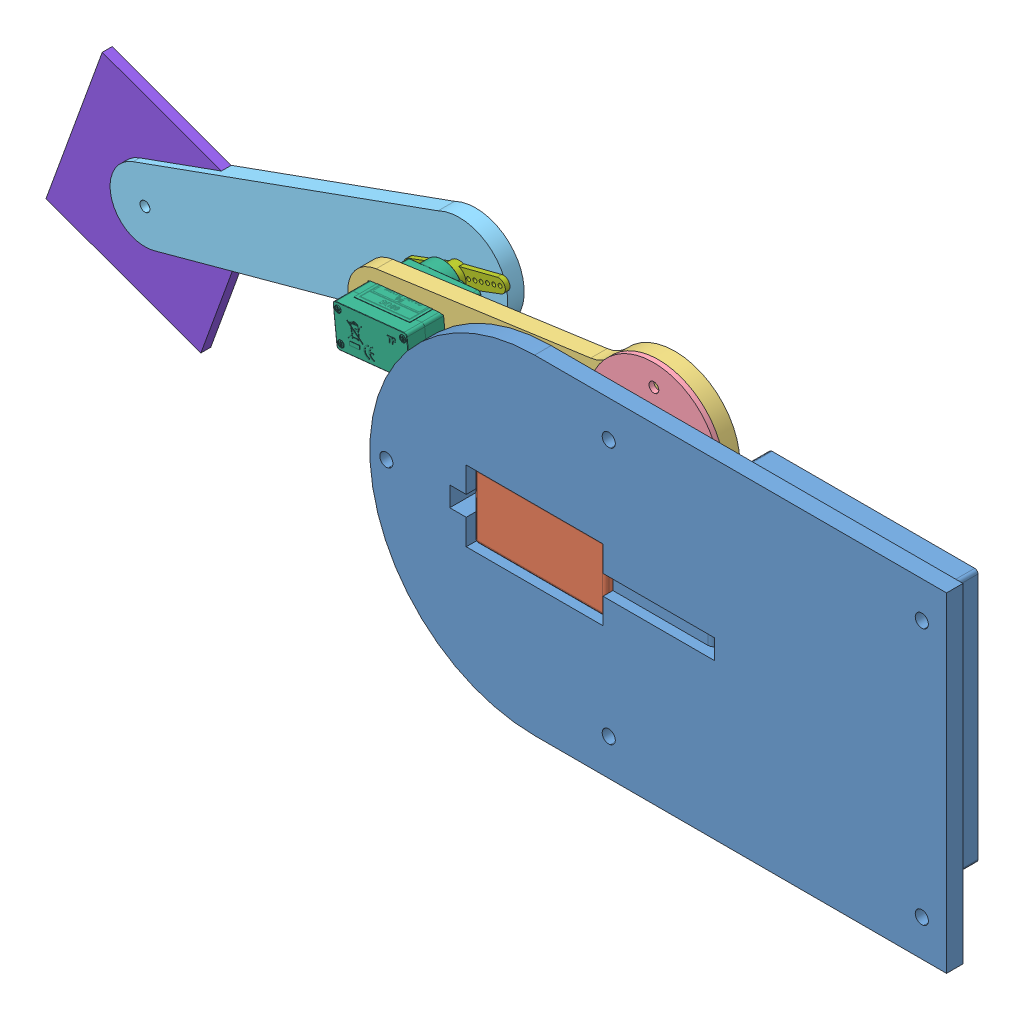
SolidWorks assembly 2 link manipulor, configuration Default. Lengths in mm.
Overall size (343.82 120.64 73.55).
8 component instances, 8 part files, 21 mates.
Components (placement in the parent):
- base-1: base [Default] at (52.7879 97.5917 136.6842) size (175 100 32)
- ServoMG996R-1: ServoMG996R [Default] at (52.7879 97.5917 126.5842) size (53.6 20 44.5)
- link1-1: link1 [Default] at (-0.7592 92.9782 116.0842) x (0.994435 0.105353 0) z (0 0 1) size (114.49 39.44 5)
- ServoMount-1: ServoMount [Default] at (76.5728 26.5748 121.0842) x (0.999979 -0.006541 0) z (0 0 1) size (40 40 5.5)
- link2-1: link2 [Default] at (-88.917 73.2046 95.1342) x (-0.953672 -0.300847 0) z (-0.300847 0.953672 0) size (125.32 5 29.44)
- SG90 - Micro Servo 9g - Tower Pro.1-2: SG90 - Micro Servo 9g - Tower Pro.1 [Peça] at (-33.5163 89.6084 121.2342) x (0.994435 0.105353 0) z (-0.105353 0.994435 0) size (32.1 29.95 12.4)
- SG90 - Micro Servo 9g - Tower Pro.3-1: SG90 - Micro Servo 9g - Tower Pro.3 [Peça] at (-38.6376 89.0659 100.1342) x (0.953672 0.300847 0) z (-0.300847 0.953672 0) size (32.1 3.8 6.9)
- Kotak-1: Kotak [Default] at (-134.0048 58.9811 95.1342) x (0.341317 0.939948 0) z (0 0 1) size (50 50 3)
Mates (geometry in assembly coordinates):
- Concentric3: concentric anti-aligned: cylinder of base-1 through (28.3879 92.5917 151.6842) axis (0 0 -1) radius 1; cylinder of ServoMG996R-1 through (28.3879 92.5917 134.6842) axis (0 0 1) radius 2.2
- Concentric4: concentric anti-aligned: cylinder of base-1 through (28.3879 102.5917 151.6842) axis (0 0 -1) radius 1; cylinder of ServoMG996R-1 through (28.3879 102.5917 134.6842) axis (0 0 1) radius 2.2
- Coincident7: coincident anti-aligned: plane of base-1 through (52.7879 97.5917 136.6842) normal (0 0 -1); plane of ServoMG996R-1 through (52.7879 97.5917 136.6842) normal (0 0 1)
- Concentric5: concentric anti-aligned: cylinder of ServoMG996R-1 through (42.7879 97.5917 122.5842) axis (0 0 1) radius 3; cylinder of ServoMount-1 through (42.7879 97.5917 126.5842) axis (0 0 -1) radius 3
- Coincident8: coincident anti-aligned: plane of ServoMG996R-1 through (42.7879 97.5917 122.5842) normal (0 0 -1); plane of ServoMount-1 through (42.7879 97.5917 122.5842) normal (0 0 1)
- Concentric6: concentric anti-aligned: cylinder of link1-1 through (42.7879 97.5917 115.0842) axis (0 0 1) radius 4.5; cylinder of ServoMount-1 through (42.7879 97.5917 122.5842) axis (0 0 -1) radius 1
- Coincident9: coincident anti-aligned: plane of link1-1 through (-0.7592 92.9782 121.0842) normal (0 0 1); plane of ServoMount-1 through (42.7879 97.5917 121.0842) normal (0 0 -1)
- Coincident13: coincident anti-aligned: plane of link2-1 through (-38.6376 89.0659 100.1342) normal (0 0 1); plane of ServoMount2-1 through (-41.4225 92.5523 88.6657) normal (0 0 -1)
- Concentric13: concentric aligned: cylinder of link2-1 through (-38.6376 89.0659 100.1342) axis (0 0 -1) radius 1.05; cylinder of ServoMount2-1 through (-41.4225 92.5523 90.1657) axis (0 0 -1) radius 15
- Coincident14: coincident anti-aligned: plane of link1-1 through (-45.3252 94.2904 121.0842) normal (0.105353 -0.994435 0); plane of SG90 - Micro Servo 9g - Tower Pro.1-1 through (-46.4443 118.3601 113.5842) normal (0.162415 0.986723 0)
- Coincident15: coincident anti-aligned: plane of link1-1 through (-22.4532 96.7135 121.0842) normal (-0.994435 -0.105353 0); plane of SG90 - Micro Servo 9g - Tower Pro.1-1 through (-20.4836 113.2255 116.0842) normal (0.986723 -0.162415 0)
- Coincident16: coincident anti-aligned: plane of link1-1 through (-0.7592 92.9782 116.0842) normal (0 0 -1); plane of SG90 - Micro Servo 9g - Tower Pro.1-1 through (-46.5824 117.5214 116.0842) normal (0 0 1)
- Concentric14: concentric aligned: circle of SG90 - Micro Servo 9g - Tower Pro.1-2; circle of SG90 - Micro Servo 9g - Tower Pro.3-1
- Coincident18: coincident anti-aligned: plane of link1-1 through (-44.061 82.3572 121.0842) normal (-0.105353 0.994435 0); plane of SG90 - Micro Servo 9g - Tower Pro.1-2 through (-43.2157 82.4467 131.7842) normal (0.105353 -0.994435 0)
- Coincident19: coincident anti-aligned: plane of link1-1 through (-45.3252 94.2904 121.0842) normal (0.994435 0.105353 0); plane of SG90 - Micro Servo 9g - Tower Pro.1-2 through (-45.2567 93.644 131.7842) normal (-0.994435 -0.105353 0)
- Coincident20: coincident anti-aligned: plane of link1-1 through (-0.7592 92.9782 116.0842) normal (0 0 -1); plane of SG90 - Micro Servo 9g - Tower Pro.1-2 through (-49.1848 93.2279 116.0842) normal (0 0 1)
- Coincident21: coincident anti-aligned: plane of SG90 - Micro Servo 9g - Tower Pro.1-2 through (-38.6376 89.0659 101.9342) normal (0 0 -1); plane of SG90 - Micro Servo 9g - Tower Pro.3-1 through (-38.6376 89.0659 101.9342) normal (0 0 1)
- Concentric15: concentric aligned: circle of link2-1; circle of SG90 - Micro Servo 9g - Tower Pro.3-1
- Coincident23: coincident anti-aligned: plane of link2-1 through (-38.6376 89.0659 100.1342) normal (0 0 1); plane of SG90 - Micro Servo 9g - Tower Pro.3-1 through (-38.6376 89.0659 100.1342) normal (0 0 -1)
- Concentric18: concentric anti-aligned: circle of link2-1; circle of SG90 - Micro Servo 9g - Tower Pro.3-1
- Coincident24: coincident aligned: circle of link2-1; circle of Kotak-1
